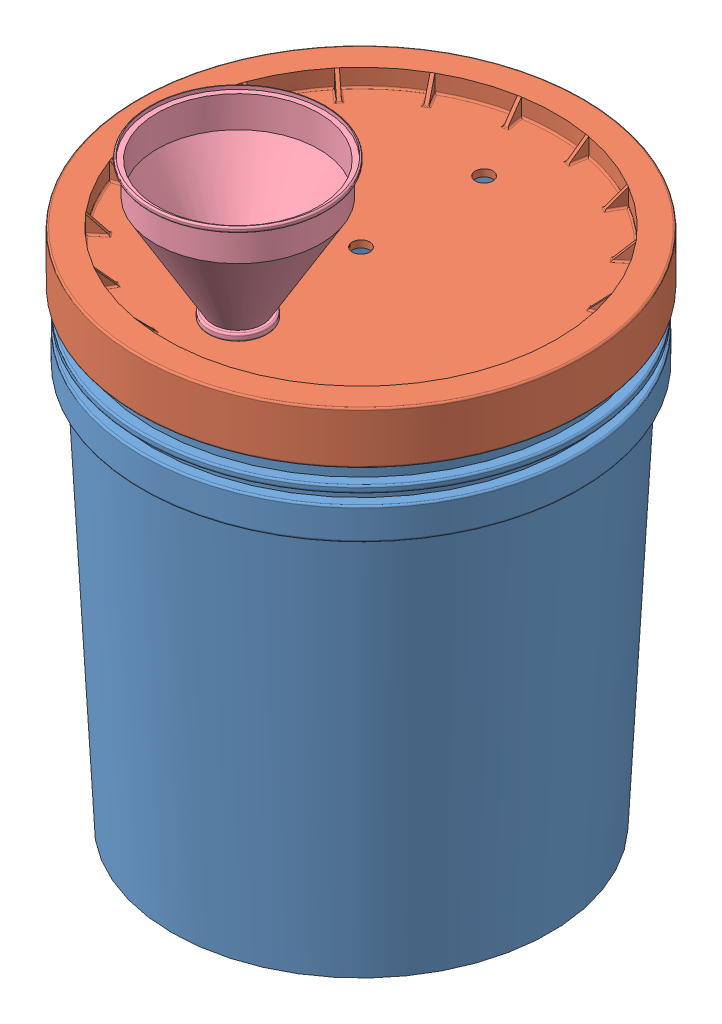
SolidWorks assembly Coolant System, configuration Default. Lengths in mm.
Overall size (321.54 462.28 321.54).
6 component instances, 5 part files, 7 mates.
Components (placement in the parent):
- Bucket with Lid-1: Bucket with Lid [Default] at origin size (321.54 373.38 321.54)
  - Bucket-1: Bucket [Default] at origin size (316.46 368.3 316.46)
  - Lid^Bucket with Lid-1: Lid^Bucket with Lid [Default] at origin size (321.54 37.48 321.54) (virtual)
- Pump-2: Pump [Default] at (0 13.35 -18.742) size (72.96 119.38 106.18)
- Funnel-1: Funnel [Default] at (0 462.28 88.9) size (127 381 127)
- Filter-1: Filter [9317T661] at (0 363.22 88.9) size (38.1 2.54 38.1)
Mates (geometry in assembly coordinates):
- Coincident1: coincident anti-aligned: plane of Bucket with Lid-1/Bucket-1 through (130.0114 13.35 0) normal (0 1 0); plane of Pump-2 through (33.02 13.35 33.709) normal (0 -1 0)
- Coincident2: coincident aligned: plane of Bucket with Lid-1 through (0 0 0) normal (1 0 0); plane of Pump-2 through (0 13.35 -18.742) normal (1 0 0)
- Concentric1: concentric anti-aligned: circle of Bucket with Lid-1/Bucket-1; circle of Pump-2
- Coincident3: coincident anti-aligned: plane of Bucket with Lid-1/Lid^Bucket with Lid-1 through (0 360.68 0) normal (0 1 0); plane of Funnel-1 through (21.35 360.68 88.9) normal (0 -1 0)
- Concentric2: concentric aligned: circle of Bucket with Lid-1/Lid^Bucket with Lid-1; circle of Funnel-1
- Coincident4: coincident anti-aligned: plane of Funnel-1 through (21.35 361.95 88.9) normal (0 1 0); plane of Filter-1 through (0 361.95 88.9) normal (0 -1 0)
- Concentric3: concentric anti-aligned: circle of Funnel-1; circle of Filter-1
